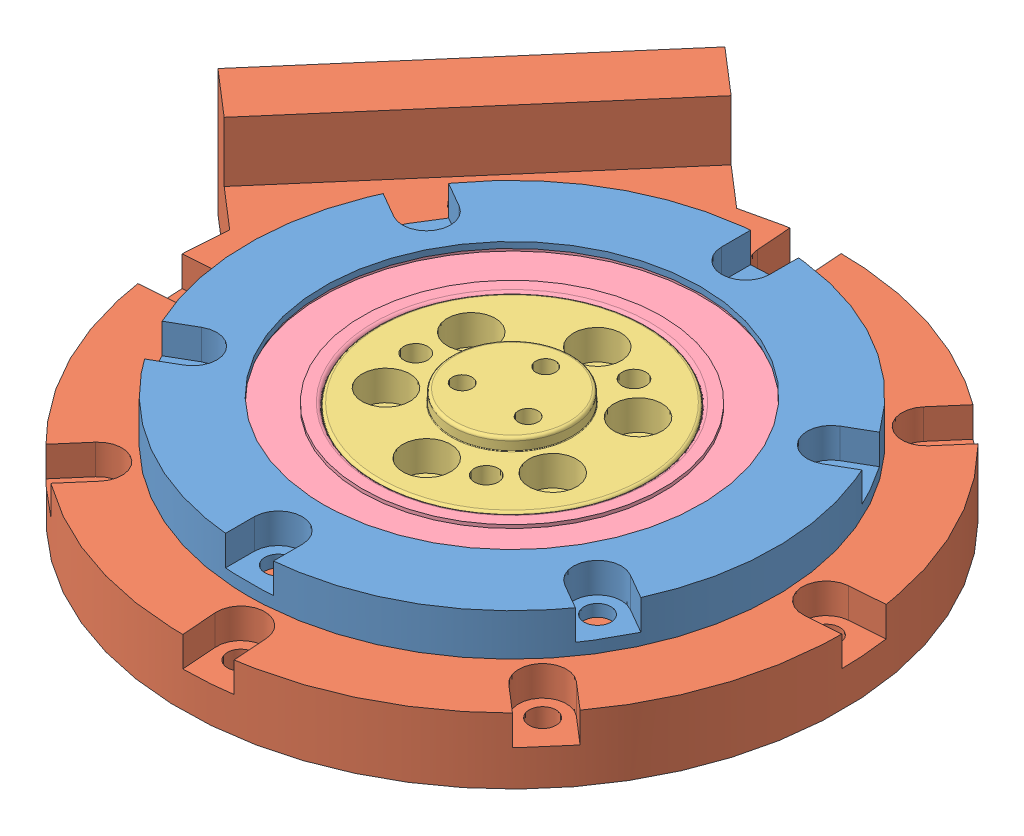
SolidWorks assembly Hip Assemble v2, configuration 기본. Lengths in mm.
Overall size (162.71 21 161.67).
4 component instances, 4 part files, 14 mates.
Components (placement in the parent):
- Actuator Jig Bearing Cap v2-1: Actuator Jig Bearing Cap v2 [기본] at (-10.3764 1.5523 88) size (88 7 88)
- Actuator Jig v2-1: Actuator Jig v2 [기본] at (-10.3764 -9.4477 88) x (0.757314 0 0.653051) z (-0.653051 0 0.757314) size (120 21 110)
- Load Flange v2-1: Load Flange v2 [기본] at (-10.3764 -9.4477 88) x (-0.446712 0 0.894678) z (-0.894678 0 -0.446712) size (50 17 50)
- C-SE6909ZZ.stp-1: C-SE6909ZZ.stp [기본] at (-10.3764 -4.4477 88) x (0 1 0) z (0.397226 0 0.917721) size (12 68 68)
Mates (geometry in assembly coordinates):
- 동심1: concentric anti-aligned: circle of Actuator Jig v2-1; circle of NSK_7909A5-1/7909A5 Outer ring-1
- 일치2: coincident anti-aligned: plane of Actuator Jig v2-1 through (-10.3764 -4.4477 88) normal (0 1 0); plane of NSK_7909A5-1/7909A5 Inner ring-1 through (12.7236 -4.4477 88) normal (0 -1 0)
- 일치3: coincident anti-aligned: plane of Actuator Jig Bearing Cap v2-1 through (-10.3764 7.5523 88) normal (0 -1 0); plane of NSK_7909A5-1/7909A5 Inner ring-1 through (16.0236 7.5523 88) normal (0 1 0)
- 동심2: concentric anti-aligned: circle of Actuator Jig Bearing Cap v2-1; circle of NSK_7909A5-1/7909A5 Outer ring-1
- 동심3: concentric anti-aligned: circle of NSK_7909A5-1/7909A5 Inner ring-1; circle of Load Flange v2-1
- 일치5: coincident anti-aligned: plane of NSK_7909A5-1/7909A5 Inner ring-1 through (12.7236 -4.4477 88) normal (0 -1 0); plane of Load Flange v2-1 through (-10.3764 -4.4477 88) normal (0 1 0)
- 동심4: concentric anti-aligned: circle of NSK_7909A5-1/7909A5 Inner ring-1; circle of Hip Link v2-2
- 일치6: coincident anti-aligned: plane of Load Flange v2-1 through (-10.3764 9.5523 88) normal (0 1 0); plane of Hip Link v2-2 through (-10.3764 12.5523 88) normal (0 -1 0)
- 동심6: concentric aligned: circle of Actuator Jig Bearing Cap v2-1; circle of Actuator Jig v2-1
- 동심8: concentric anti-aligned: cylinder of Load Flange v2-1 through (-10.3764 -4.4477 88) axis (0 -1 0) radius 25; cylinder of C-SE6909ZZ.stp-1 through (-10.3764 7.5523 88) axis (0 1 0) radius 34
- 동심9: concentric anti-aligned: cylinder of Actuator Jig v2-1 through (-10.3764 1.5523 88) axis (0 -1 0) radius 34; cylinder of C-SE6909ZZ.stp-1 through (-10.3764 7.5523 88) axis (0 1 0) radius 34
- 일치8: coincident anti-aligned: plane of Actuator Jig v2-1 through (-10.3764 -4.4477 88) normal (0 1 0); plane of C-SE6909ZZ.stp-1 through (-33.3194 -4.4477 97.9306) normal (0 -1 0)
- 일치9: coincident anti-aligned: plane of Load Flange v2-1 through (-10.3764 -4.4477 88) normal (0 1 0); plane of C-SE6909ZZ.stp-1 through (-33.3194 -4.4477 97.9306) normal (0 -1 0)
- 일치10: coincident anti-aligned: plane of Actuator Jig Bearing Cap v2-1 through (-10.3764 7.5523 88) normal (0 -1 0); plane of C-SE6909ZZ.stp-1 through (-39.514 7.5523 100.6119) normal (0 1 0)
